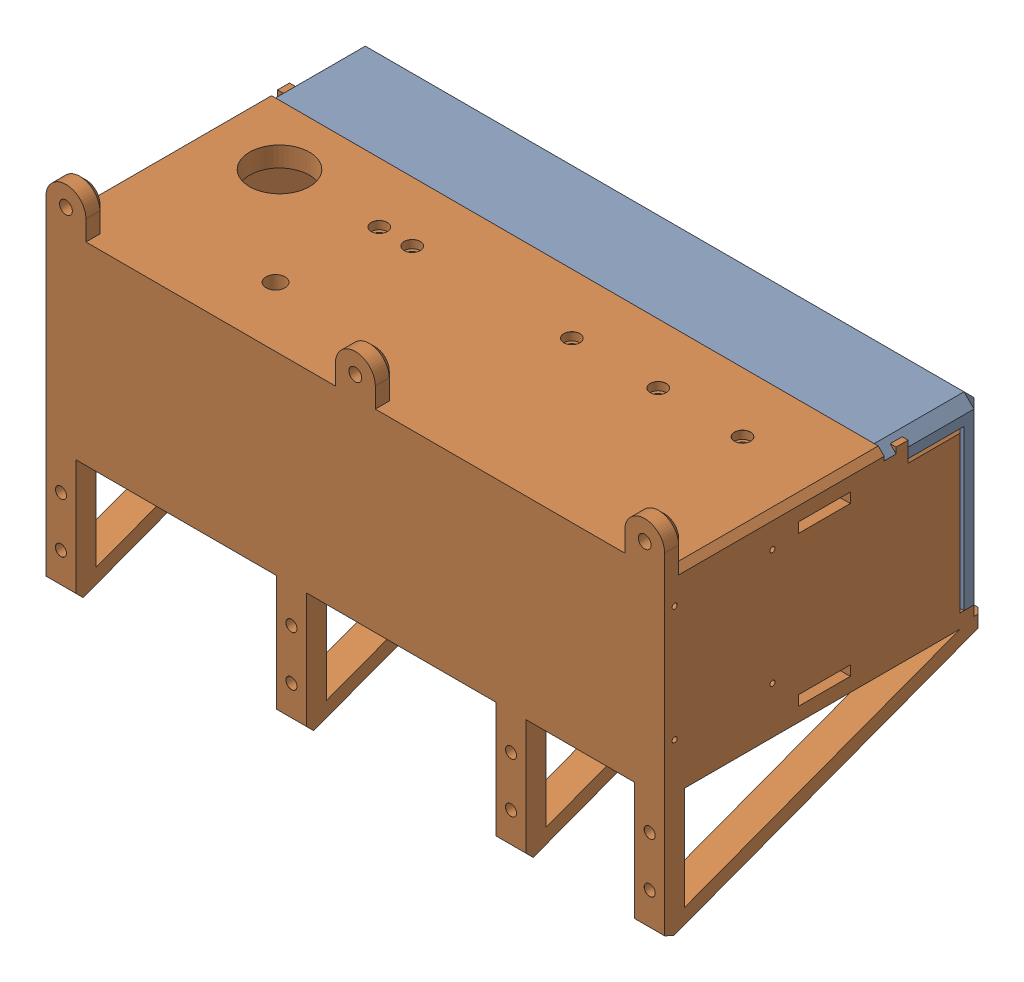
SolidWorks assembly PLA_BoxWithSpout_71025, configuration Default. Lengths in mm.
Overall size (310 181.5 160).
4 component instances, 4 part files, 21 mates.
Components (placement in the parent):
- PLA_BoxWalls_725-2: PLA_BoxWalls_725 [Default] at (-310 0 0) size (310 181.5 160)
- LED Array Housing-1: LED Array Housing [Default] at (-253 -20.4638 -98.0066) x (0 0 -1) z (0 -1 0) size (55 60 58)
- Spec_Mounts_71525-1: Spec_Mounts_71525 [Default] at (-28.5 -46 -80) x (-1 0 0) z (0 0 -1) size (110.5 57 34)
- spout_-3: spout_ [Default] at (-187.8416 -113.8132 -62.1258) x (1 0 0) z (0 -1 0) size (6.35 6.35 23) (hidden)
Mates (geometry in assembly coordinates):
- Coincident21: coincident anti-aligned: line of spout_-1 through (-300 0 0) axis (0 0 -1); line of box tabs-2 through (-310 0 -10) axis (0 0 1)
- Coincident22: coincident anti-aligned: line of spout_-1 through (0 0 0) axis (-1 0 0); line of box tabs-2 through (-310 0 0) axis (1 0 0)
- Coincident27: coincident aligned: plane of spout_-1 through (0 0 0) normal (1 0 0)
- Coincident28: coincident aligned: plane of spout_-1 through (0 0 0) normal (0 0 1)
- Coincident29: coincident aligned: plane of spout_-1 through (0 0 0) normal (0 1 0)
- Coincident30: coincident aligned: plane of PLA_BoxWalls_725-2 through (0 0 0) normal (0 0 1)
- Coincident31: coincident aligned: plane of PLA_BoxWalls_725-2 through (0 0 0) normal (1 0 0)
- Coincident32: coincident aligned: plane of PLA_BoxWalls_725-2 through (0 0 0) normal (0 1 0)
- Concentric2: concentric aligned: circle of PLA_BoxWalls_725-2; circle of Spec_Mounts_71525-1
- Coincident40: coincident anti-aligned: circle of PLA_BoxWalls_725-2; plane of Spec_Mounts_71525-1 through (-95.75 -6 -80) normal (0 1 0)
- Concentric3: concentric aligned: circle of PLA_BoxWalls_725-2; circle of Spec_Mounts_71525-1
- Concentric9: concentric aligned: circle of PLA_BoxWalls_725-2; circle of spout_-3
- Concentric10: concentric anti-aligned: circle of PLA_BoxWalls_725-2; circle of spout_-3
- Coincident44: coincident anti-aligned: line of PLA_BoxWalls_725-2 through (-310 0 -10) axis (0 0 -1); line of box tabs-2 through (-310 0 -10) axis (0 0 1)
- Coincident45: coincident anti-aligned: line of PLA_BoxWalls_725-2 through (0 0 0) axis (-1 0 0); line of box tabs-2 through (-310 0 0) axis (1 0 0)
- Coincident46: coincident anti-aligned: line of PLA_BoxWalls_725-2 through (0 0 0) axis (-1 0 0); line of box tabs-3 through (-158.4807 0 0) axis (1 0 0)
- Parallel1: parallel anti-aligned: line of PLA_BoxWalls_725-2 through (-310 0 -10) axis (0 0 -1); line of box tabs-3 through (-158.4807 0 -10) axis (0 0 1)
- Coincident48: coincident anti-aligned: plane of PLA_BoxWalls_725-2 through (-310 -6 0) normal (0 -1 0); plane of LED Array Housing-1 through (-253 -6 -98.0066) normal (0 1 0)
- Concentric11: concentric aligned: circle of PLA_BoxWalls_725-2; circle of LED Array Housing-1
- Coincident49: coincident aligned: line of PLA_BoxWalls_725-2 through (0 0 0) axis (-1 0 0); line of box tabs-1 through (0 0 0) axis (-1 0 0)
- Coincident50: coincident aligned: line of PLA_BoxWalls_725-2 through (0 0 -10) axis (0 0 -1); line of box tabs-1 through (0 0 0) axis (0 0 -1)
